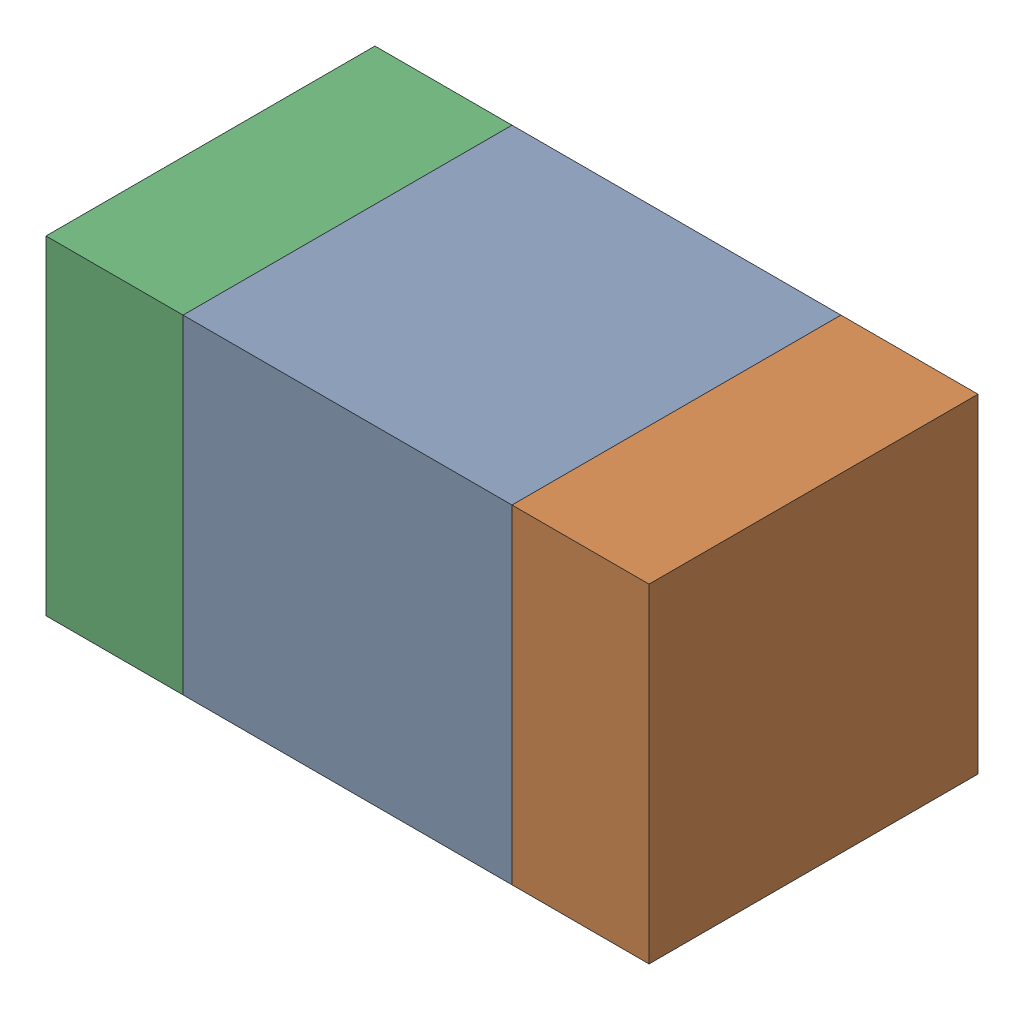
SolidWorks assembly C300_1PCB, configuration Default. Lengths in mm.
Overall size (1.1 0.6 0.6).
6 component instances, 2 part files, 0 mates.
Components (placement in the parent):
- 761606048-1: 761606048 [Default] at (148.3 103.8 0) size (0.6 0.6 0.6)
  - Extruded_9-1: Extruded_9 [Default] at origin size (0.6 0.6 0.6)
- 854785160-1: 854785160 [Default] at (148.725 103.8 0) size (0.25 0.6 0.6)
  - Extruded_19-1: Extruded_19 [Default] at origin size (0.25 0.6 0.6)
- 854785160-2: 854785160 [Default] at (147.875 103.8 0) size (0.25 0.6 0.6)
  - Extruded_19-1: Extruded_19 [Default] at origin size (0.25 0.6 0.6)
